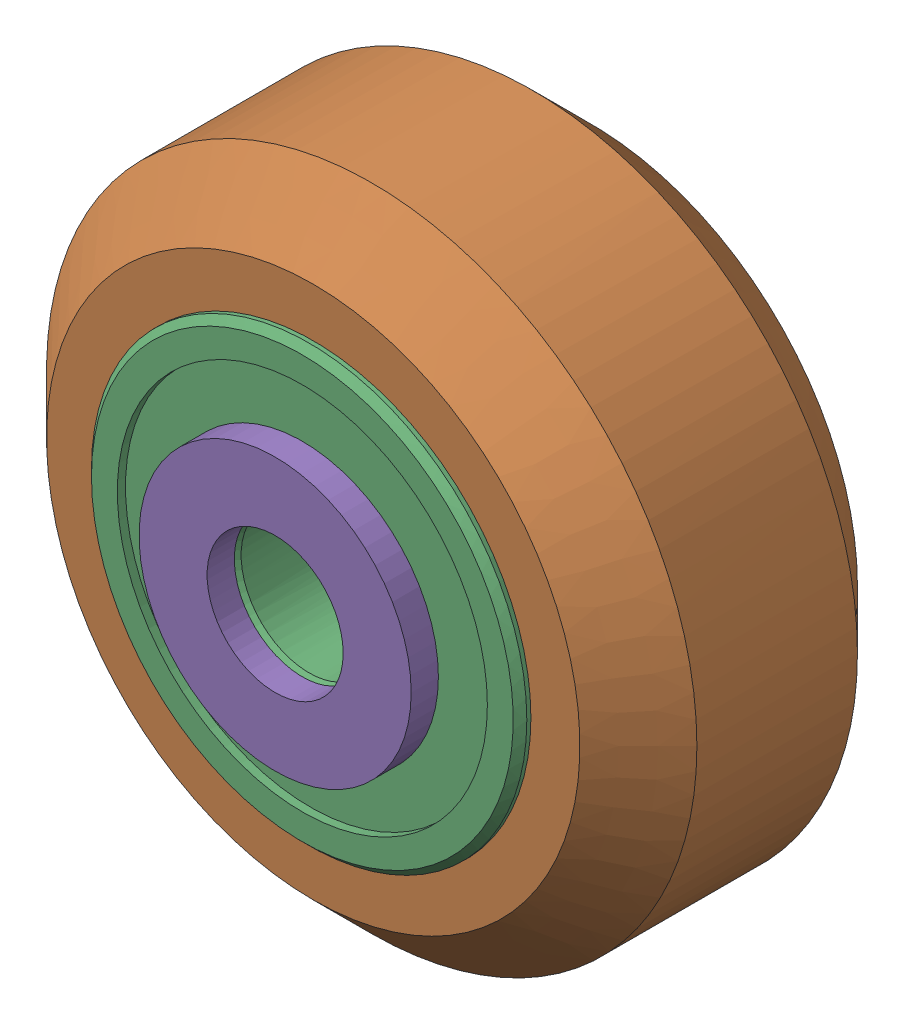
SolidWorks assembly Xtreme Solid V Wheel Kit Assembly, configuration Default. Lengths in mm.
Overall size (23.9 23.9 13).
6 component instances, 3 part files, 0 mates.
Components (placement in the parent):
- Precision Shim - 10x5x1mm-1: Precision Shim - 10x5x1mm [Default] at origin size (10 10 1)
- Xtreme Solid V Wheel Assembly-1: Xtreme Solid V Wheel Assembly [Default] at (45.15 25 -23.5) size (23.9 23.9 11)
  - Xtreme Solid V Wheel-1: Xtreme Solid V Wheel [Default] at (-45.15 -25 30) x (0 0 1) z (-1 0 0) size (10.2 23.9 23.9)
  - Wheel+Kit+-+5x16x5mm+Sealed+Radial+Ball+Bearing.step.f3d-1: Wheel+Kit+-+5x16x5mm+Sealed+Radial+Ball+Bearing.step.f3d [Default] at (-45.15 -25 30) x (0 1 0) z (-1 0 0) size (16 5 16)
  - Wheel+Kit+-+5x16x5mm+Sealed+Radial+Ball+Bearing.step.f3d-2: Wheel+Kit+-+5x16x5mm+Sealed+Radial+Ball+Bearing.step.f3d [Default] at (-45.15 -25 30) x (0 1 0) z (1 0 0) size (16 5 16)
- Precision Shim - 10x5x1mm-2: Precision Shim - 10x5x1mm [Default] at (0 0 12) size (10 10 1)
